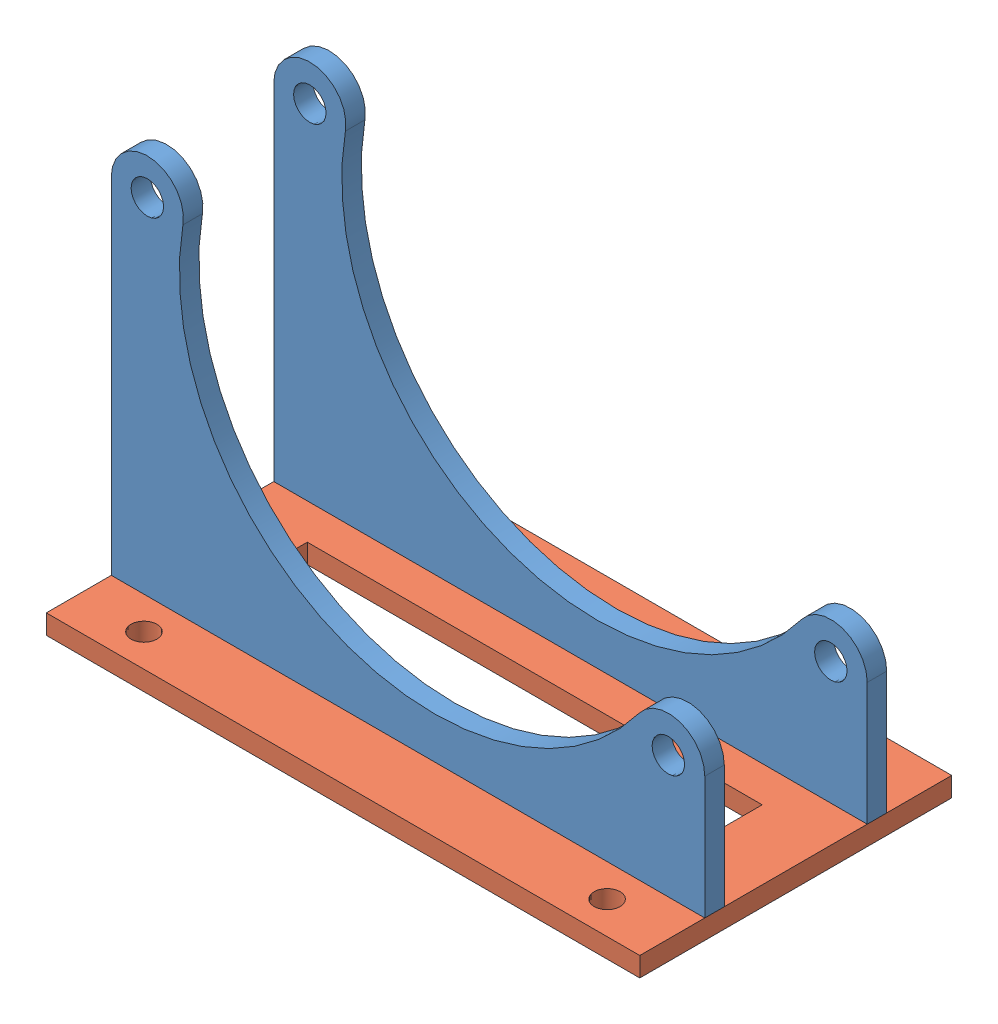
SolidWorks assembly Assem1, configuration Default. Lengths in mm.
Overall size (182.65 123.37 96).
3 component instances, 2 part files, 6 mates.
Components (placement in the parent):
- mount-1: mount [Default] at (17.5894 72.1853 146.5442) size (182.65 123.37 6)
- base plate-1: base plate [Default] at (45.775 37.2793 174.5442) x (1 0 0) z (0 1 0) size (182.65 96 6)
- mount-2: mount [Default] at (17.5894 72.1853 196.5442) size (182.65 123.37 6)
Mates (geometry in assembly coordinates):
- Coincident1: coincident anti-aligned: plane of base plate-1 through (-15.55 43.2793 202.5442) normal (0 0 -1); plane of mount-2 through (125.8945 81.0663 202.5442) normal (0 0 1)
- Coincident2: coincident aligned: plane of base plate-1 through (45.775 37.2793 174.5442) normal (0 -1 0); plane of mount-2 through (-15.5475 37.2793 202.5442) normal (0 -1 0)
- Coincident3: coincident anti-aligned: plane of mount-2 through (107.1 37.2793 202.5442) normal (1 0 0); plane of base plate-1 through (107.1 43.2793 202.5442) normal (-1 0 0)
- Coincident4: coincident anti-aligned: plane of mount-1 through (125.8945 81.0663 152.5442) normal (0 0 1); plane of base plate-1 through (107.1 43.2793 152.5442) normal (0 0 -1)
- Coincident5: coincident anti-aligned: plane of mount-1 through (107.1 37.2793 152.5442) normal (1 0 0); plane of base plate-1 through (107.1 43.2793 146.5442) normal (-1 0 0)
- Coincident6: coincident aligned: plane of mount-1 through (-15.5475 37.2793 152.5442) normal (0 -1 0); plane of base plate-1 through (45.775 37.2793 174.5442) normal (0 -1 0)
